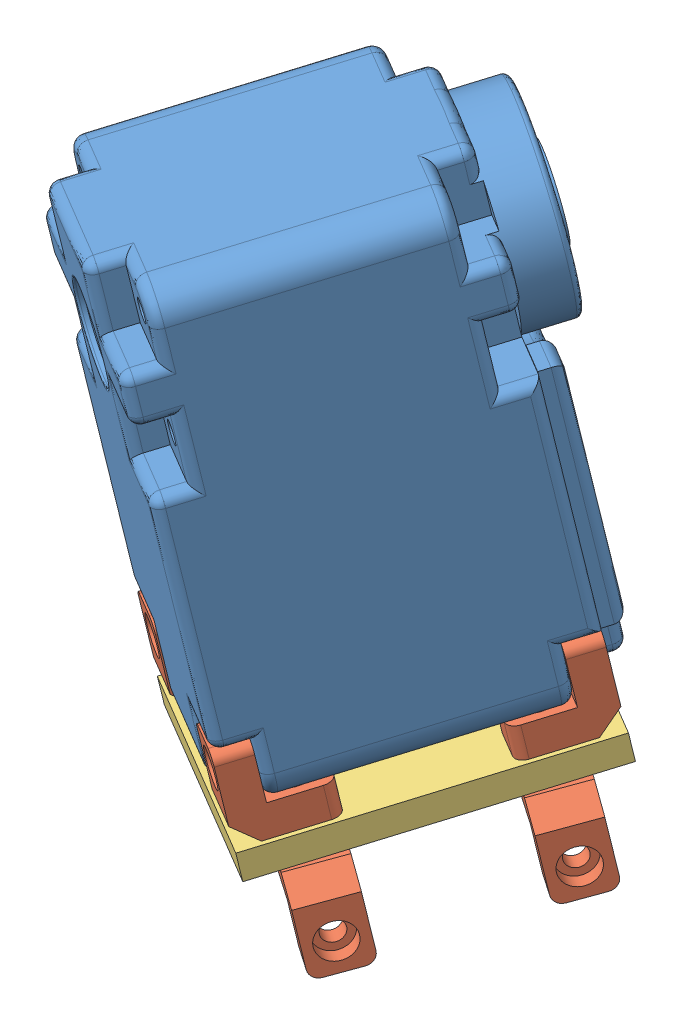
SolidWorks assembly Assem2, configuration Default. Lengths in mm.
Overall size (44.26 64.43 47.42).
10 component instances, 3 part files, 24 mates.
Components (placement in the parent):
- herkulex_motor-1: herkulex_motor [Default] at (-26.3326 -9.852 -28.0574) x (-0.849449 -0.053167 -0.524986) z (0.144935 -0.980154 -0.135247) size (24 34.2 45)
- L joint-1: L joint [Default] at (-16.1429 -30.4995 -30.1675) x (0.507376 0.190974 -0.840297) z (0.144935 -0.980154 -0.135247) size (8.2 5.1 8.2)
- L joint-2: L joint [Default] at (-31.433 -31.4565 -39.6173) x (0.507376 0.190974 -0.840297) z (0.144935 -0.980154 -0.135247) size (8.2 5.1 8.2)
- L joint-3: L joint [Default] at (-0.1411 -25.8359 -46.8169) x (-0.507376 -0.190974 0.840297) z (0.144935 -0.980154 -0.135247) size (8.2 5.1 8.2)
- L joint-4: L joint [Default] at (-15.4312 -26.793 -56.2667) x (-0.507376 -0.190974 0.840297) z (0.144935 -0.980154 -0.135247) size (8.2 5.1 8.2)
- arm plate-3: arm plate [Default] at (-14.8749 -33.8738 -45.0207) x (0.507376 0.190974 -0.840297) z (0.849449 0.053167 0.524986) size (29.04 2.5 24.1)
- L joint-5: L joint [Default] at (1.1218 -34.1822 -47.825) x (-0.817166 -0.041505 -0.574907) z (-0.144935 0.980154 0.135247) size (8.2 5.1 8.2)
- L joint-6: L joint [Default] at (-8.0109 -37.6197 -32.6997) x (-0.817166 -0.041505 -0.574907) z (-0.144935 0.980154 0.135247) size (8.2 5.1 8.2)
- L joint-7: L joint [Default] at (-30.174 -39.7984 -40.6611) x (0.854934 0.055248 0.515786) z (-0.144935 0.980154 0.135247) size (8.2 5.1 8.2)
- L joint-8: L joint [Default] at (-21.0412 -36.3609 -55.7865) x (0.854934 0.055248 0.515786) z (-0.144935 0.980154 0.135247) size (8.2 5.1 8.2)
Mates (geometry in assembly coordinates):
- Concentric2: concentric aligned: cylinder of herkulex_motor-1 through (-15.1835 -28.0885 -28.1274) axis (0.507376 0.190974 -0.840297) radius 1; cylinder of L joint-1 through (-16.249 -28.4896 -26.3628) axis (0.507376 0.190974 -0.840297) radius 1
- Coincident6: coincident anti-aligned: plane of herkulex_motor-1 through (-24.1326 -8.8811 -32.7359) normal (-0.507376 -0.190974 0.840297); plane of L joint-1 through (-11.1329 -29.8304 -29.6477) normal (0.507376 0.190974 -0.840297)
- Concentric3: concentric anti-aligned: cylinder of herkulex_motor-1 through (-30.4735 -29.0455 -37.5772) axis (0.507376 0.190974 -0.840297) radius 1; cylinder of L joint-4 through (-14.6941 -23.1062 -63.7104) axis (-0.507376 -0.190974 0.840297) radius 1
- Concentric4: concentric anti-aligned: cylinder of herkulex_motor-1 through (-15.1835 -28.0885 -28.1274) axis (0.507376 0.190974 -0.840297) radius 1; cylinder of L joint-3 through (0.5959 -22.1492 -54.2607) axis (-0.507376 -0.190974 0.840297) radius 1
- Coincident7: coincident anti-aligned: plane of herkulex_motor-1 through (-12.463 -4.4887 -52.0627) normal (0.507376 0.190974 -0.840297); plane of L joint-3 through (-3.7954 -25.7091 -51.652) normal (-0.507376 -0.190974 0.840297)
- Concentric7: concentric anti-aligned: cylinder of herkulex_motor-1 through (-30.4735 -29.0455 -37.5772) axis (0.507376 0.190974 -0.840297) radius 1; cylinder of L joint-2 through (-29.7632 -28.7782 -38.7536) axis (-0.507376 -0.190974 0.840297) radius 1.7
- Coincident12: coincident anti-aligned: plane of herkulex_motor-1 through (-24.1326 -8.8811 -32.7359) normal (-0.507376 -0.190974 0.840297); plane of L joint-2 through (-26.423 -30.7874 -39.0975) normal (0.507376 0.190974 -0.840297)
- Coincident13: coincident anti-aligned: plane of herkulex_motor-1 through (-12.463 -4.4887 -52.0627) normal (0.507376 0.190974 -0.840297); plane of L joint-4 through (-19.0855 -26.6662 -61.1017) normal (-0.507376 -0.190974 0.840297)
- Coincident14: coincident aligned: plane of L joint-1 through (-11.1329 -29.8304 -29.6477) normal (0.849449 0.053167 0.524986); plane of L joint-3 through (0.5367 -25.438 -48.9746) normal (0.849449 0.053167 0.524986)
- Parallel5: parallel aligned: plane of L joint-3 through (0.5367 -25.438 -48.9746) normal (0.849449 0.053167 0.524986); plane of L joint-4 through (-14.7533 -26.395 -58.4243) normal (0.849449 0.053167 0.524986)
- Parallel6: parallel aligned: plane of L joint-1 through (-11.1329 -29.8304 -29.6477) normal (0.849449 0.053167 0.524986); plane of L joint-2 through (-26.423 -30.7874 -39.0975) normal (0.849449 0.053167 0.524986)
- Coincident19: coincident aligned: plane of L joint-1 through (-11.1329 -29.8304 -29.6477) normal (0.849449 0.053167 0.524986); plane of L joint-3 through (0.5367 -25.438 -48.9746) normal (0.849449 0.053167 0.524986)
- Parallel8: parallel aligned: plane of herkulex_motor-1 through (3.5283 -24.9493 -53.0074) normal (0.849449 0.053167 0.524986); plane of L joint-3 through (0.5367 -25.438 -48.9746) normal (0.849449 0.053167 0.524986)
- Concentric9: concentric anti-aligned: cylinder of L joint-1 through (-11.2914 -34.4873 -33.7769) axis (-0.144935 0.980154 0.135247) radius 1; cylinder of arm plate-3 through (-11.5958 -32.429 -33.4929) axis (0.144935 -0.980154 -0.135247) radius 1
- Coincident21: coincident anti-aligned: plane of L joint-3 through (-1.8385 -28.0767 -54.5786) normal (0.144935 -0.980154 -0.135247); plane of arm plate-3 through (-14.5594 -31.0255 -46.8402) normal (-0.144935 0.980154 0.135247)
- Parallel9: parallel aligned: plane of herkulex_motor-1 through (-16.8584 -26.2253 -65.6071) normal (-0.849449 -0.053167 -0.524986); plane of arm plate-3 through (-24.0507 -34.0926 -53.2681) normal (-0.849449 -0.053167 -0.524986)
- Concentric10: concentric aligned: cylinder of arm plate-3 through (-2.463 -28.9915 -48.6183) axis (0.144935 -0.980154 -0.135247) radius 1; cylinder of L joint-5 through (-2.405 -29.3835 -48.6724) axis (0.144935 -0.980154 -0.135247) radius 1
- Coincident23: coincident anti-aligned: plane of arm plate-3 through (-14.1971 -33.4759 -47.1783) normal (0.144935 -0.980154 -0.135247); plane of L joint-5 through (0.9712 -31.7079 -43.7366) normal (-0.144935 0.980154 0.135247)
- Concentric11: concentric: cylinder of arm plate-3 through (-27.5637 -33.784 -40.785) axis (0.144935 -0.980154 -0.135247) radius 1; cylinder of L joint-7 through (-26.7564 -39.2432 -41.5383) axis (0.144935 -0.980154 -0.135247) radius 1.7
- Concentric12: concentric: cylinder of arm plate-3 through (-17.7531 -29.9485 -58.068) axis (0.144935 -0.980154 -0.135247) radius 1; cylinder of L joint-8 through (-17.1588 -33.9671 -58.6225) axis (0.144935 -0.980154 -0.135247) radius 1.7
- Concentric13: concentric: cylinder of arm plate-3 through (-12.2736 -32.827 -31.3353) axis (0.144935 -0.980154 -0.135247) radius 1; cylinder of L joint-6 through (-11.1132 -40.6747 -32.4182) axis (0.144935 -0.980154 -0.135247) radius 1.7
- Coincident24: coincident anti-aligned: plane of arm plate-3 through (-14.1971 -33.4759 -47.1783) normal (0.144935 -0.980154 -0.135247); plane of L joint-8 through (-20.8228 -32.2173 -63.4002) normal (-0.144935 0.980154 0.135247)
- Coincident25: coincident anti-aligned: plane of arm plate-3 through (-14.8749 -33.8738 -45.0207) normal (0.144935 -0.980154 -0.135247); plane of L joint-7 through (-30.6334 -36.0527 -46.1172) normal (-0.144935 0.980154 0.135247)
- Coincident26: coincident anti-aligned: plane of arm plate-3 through (-14.8749 -33.8738 -45.0207) normal (0.144935 -0.980154 -0.135247); plane of L joint-6 through (-8.8395 -35.5434 -26.4537) normal (-0.144935 0.980154 0.135247)
